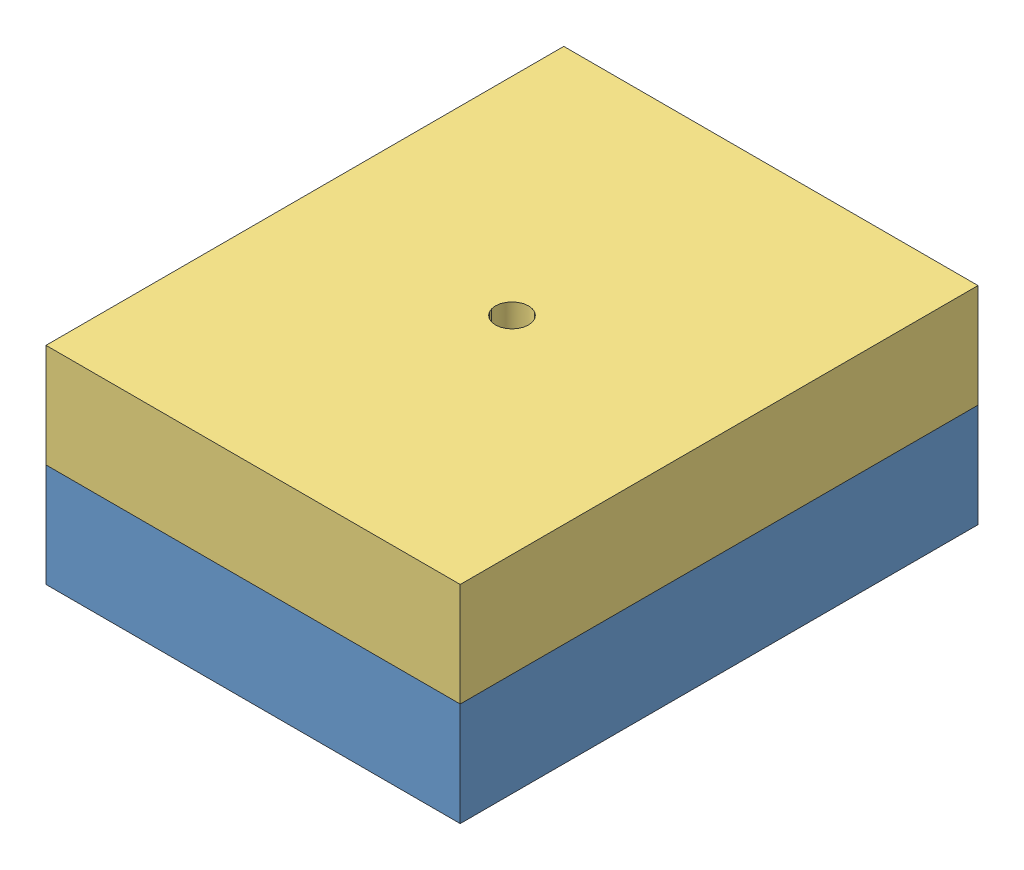
SolidWorks assembly Montagem Bloco, configuration Valor predeterminado. Lengths in mm.
Overall size (200 100 250).
14 component instances, 3 part files, 21 mates.
Components (placement in the parent):
- Cavidade Inferior-1: Cavidade Inferior [Valor predeterminado] at origin size (200 50 250)
- Grampo com Contracao-1: Grampo com Contracao [Valor predeterminado] at (-87.25 50 30) size (77.25 6.7 10.3)
- Grampo com Contracao-2: Grampo com Contracao [Valor predeterminado] at (-87.25 50 60) size (77.25 6.7 10.3)
- Grampo com Contracao-3: Grampo com Contracao [Valor predeterminado] at (-87.25 50 90) size (77.25 6.7 10.3)
- Grampo com Contracao-7: Grampo com Contracao [Valor predeterminado] at (-87.25 50 209.7) size (77.25 6.7 10.3)
- Grampo com Contracao-8: Grampo com Contracao [Valor predeterminado] at (-87.25 50 179.7) size (77.25 6.7 10.3)
- Grampo com Contracao-9: Grampo com Contracao [Valor predeterminado] at (-87.25 50 149.7) size (77.25 6.7 10.3)
- Grampo com Contracao-10: Grampo com Contracao [Valor predeterminado] at (87.25 50 40.3) x (-1 0 0) z (0 0 -1) size (77.25 6.7 10.3)
- Grampo com Contracao-11: Grampo com Contracao [Valor predeterminado] at (87.25 50 100.3) x (-1 0 0) z (0 0 -1) size (77.25 6.7 10.3)
- Grampo com Contracao-12: Grampo com Contracao [Valor predeterminado] at (87.25 50 70.3) x (-1 0 0) z (0 0 -1) size (77.25 6.7 10.3)
- Grampo com Contracao-13: Grampo com Contracao [Valor predeterminado] at (87.25 50 220) x (-1 0 0) z (0 0 -1) size (77.25 6.7 10.3)
- Grampo com Contracao-14: Grampo com Contracao [Valor predeterminado] at (87.25 50 190) x (-1 0 0) z (0 0 -1) size (77.25 6.7 10.3)
- Grampo com Contracao-15: Grampo com Contracao [Valor predeterminado] at (87.25 50 160) x (-1 0 0) z (0 0 -1) size (77.25 6.7 10.3)
- Cavidade Superior-1: Cavidade Superior [Valor predeterminado] at (0 50 250) size (200 51 250)
Mates (geometry in assembly coordinates):
- Distância1: distance = 30 mm aligned: plane of Grampo com Contracao-1 through (-87.25 50 30) normal (0 0 -1); plane of Cavidade Inferior-1 through (-100 50 0) normal (0 0 -1)
- Distância7: distance = 10 mm: plane of assembly through (0 0 0) normal (1 0 0); plane of assembly; plane of Grampo com Contracao-1 through (-10 50 40.3) normal (1 0 0)
- Coincidente4: coincident aligned: plane of Cavidade Inferior-1 through (0 50 0) normal (0 1 0); plane of Grampo com Contracao-1 through (-41.93 50 40.3) normal (0 1 0)
- Distância2: distance = 60 mm aligned: plane of Grampo com Contracao-2 through (-87.25 50 60) normal (0 0 -1); plane of Cavidade Inferior-1 through (-100 50 0) normal (0 0 -1)
- Coincidente6: coincident aligned: plane of Cavidade Inferior-1 through (0 50 0) normal (0 1 0); plane of Grampo com Contracao-2 through (-41.93 50 70.3) normal (0 1 0)
- Distância8: distance = 10 mm aligned: plane of Grampo com Contracao-2 through (-10 50 70.3) normal (1 0 0)
- Distância3: distance = 90 mm aligned: plane of Grampo com Contracao-3 through (-87.25 50 90) normal (0 0 -1); plane of Cavidade Inferior-1 through (-100 50 0) normal (0 0 -1)
- Coincidente9: coincident aligned: plane of Cavidade Inferior-1 through (0 50 0) normal (0 1 0); plane of Grampo com Contracao-3 through (-41.93 50 100.3) normal (0 1 0)
- Distância9: distance = 10 mm aligned: plane of Grampo com Contracao-3 through (-10 50 100.3) normal (1 0 0)
- Distância4: distance = 30 mm aligned: plane of Grampo com Contracao-7 through (-87.25 50 220) normal (0 0 1); plane of Cavidade Inferior-1 through (-100 50 250) normal (0 0 1)
- Coincidente12: coincident aligned: plane of Cavidade Inferior-1 through (0 50 0) normal (0 1 0); plane of Grampo com Contracao-7 through (-41.93 50 220) normal (0 1 0)
- Distância10: distance = 10 mm aligned: plane of Grampo com Contracao-7 through (-10 50 220) normal (1 0 0)
- Distância5: distance = 60 mm aligned: plane of Grampo com Contracao-8 through (-87.25 50 190) normal (0 0 1); plane of Cavidade Inferior-1 through (-100 50 250) normal (0 0 1)
- Coincidente15: coincident aligned: plane of Cavidade Inferior-1 through (0 50 0) normal (0 1 0); plane of Grampo com Contracao-8 through (-41.93 50 190) normal (0 1 0)
- Distância11: distance = 10 mm aligned: plane of Grampo com Contracao-8 through (-10 50 190) normal (1 0 0)
- Distância6: distance = 90 mm aligned: plane of Grampo com Contracao-9 through (-87.25 50 160) normal (0 0 1); plane of Cavidade Inferior-1 through (-100 50 250) normal (0 0 1)
- Coincidente21: coincident aligned: plane of Cavidade Inferior-1 through (0 50 0) normal (0 1 0); plane of Grampo com Contracao-9 through (-41.93 50 160) normal (0 1 0)
- Distância12: distance = 10 mm aligned: plane of Grampo com Contracao-9 through (-10 50 160) normal (1 0 0)
- Coincidente23: coincident anti-aligned: plane of Cavidade Inferior-1 through (0 50 0) normal (0 1 0); plane of Cavidade Superior-1 through (0 50 250) normal (0 -1 0)
- Coincidente24: coincident aligned: plane of Cavidade Inferior-1 through (100 50 250) normal (1 0 0); plane of Cavidade Superior-1 through (100 100 250) normal (1 0 0)
- Coincidente25: coincident aligned: plane of Cavidade Inferior-1 through (-100 50 250) normal (0 0 1); plane of Cavidade Superior-1 through (-100 100 250) normal (0 0 1)
